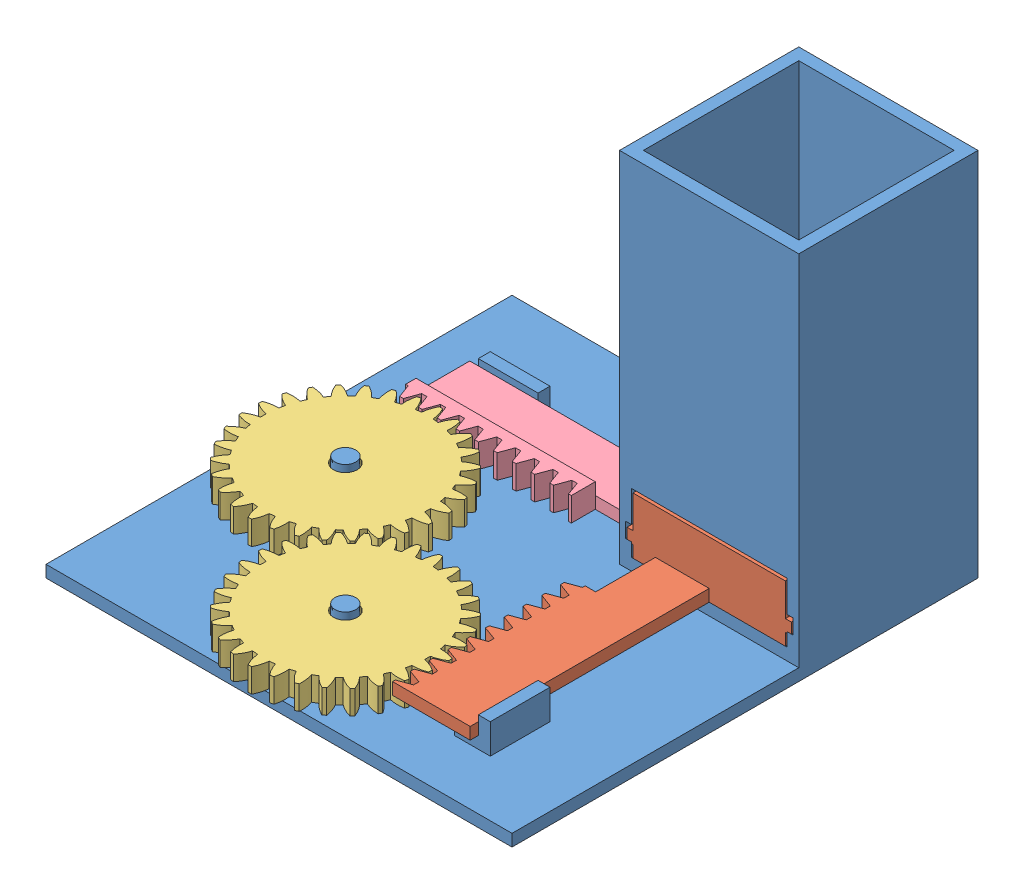
SolidWorks assembly POC_shutter, configuration Default. Lengths in mm.
Overall size (79.58 62 79.64).
5 component instances, 4 part files, 9 mates.
Components (placement in the parent):
- POC_shutter_box-1: POC_shutter_box [Default] at (21.1546 10.3571 63.6292) size (78 62 78)
- POC_shutter_wedge_w_gear-1: POC_shutter_wedge_w_gear [Default] at (95.5205 -20.2555 36.7459) x (0 0 1) z (-1 0 0) size (68 9.46 27.5)
- spur gear_am-4: spur gear_am [Metric - Spur gear 1M 30T 20PA 4FW ---S30N75H50L4N] at (17.9046 16.3571 88.2692) x (0 -1 0) z (0 0 1) size (4 31.88 32)
- spur gear_am-5: spur gear_am [Metric - Spur gear 1M 30T 20PA 4FW ---S30N75H50L4N] at (-3.4854 16.3571 66.8792) x (0 -1 0) z (0 0 1) size (4 31.88 32)
- POC_shutter_shutter_w_gear_reverse-1: POC_shutter_shutter_w_gear_reverse [Default] at (79.2798 -21.4381 18.9739) x (0 0 1) z (-1 0 0) size (27.5 4 68)
Mates (geometry in assembly coordinates):
- Symmetric2: symmetric: plane of POC_shutter_box-1 through (31.1546 10.3571 63.6292) normal (1 0 0); plane of POC_shutter_box-1 through (59.1546 10.3571 63.6292) normal (-1 0 0); plane of POC_shutter_wedge_w_gear-1 through (45.1546 14.3571 94.6292) normal (1 0 0)
- Coincident3: coincident: plane of POC_shutter_box-1 through (32.1546 10.3571 26.6292) normal (0 0 1); line of POC_shutter_wedge_w_gear-1 through (57.9046 14.3571 26.6292) axis (-1 0 0)
- Coincident8: coincident: plane of POC_shutter_box-1 through (21.1546 12.3571 63.6292) normal (0 1 0); plane of spur gear_am-4 through (17.9046 12.3571 88.2692) normal (0 -1 0)
- Coincident9: coincident: plane of POC_shutter_box-1 through (21.1546 12.3571 63.6292) normal (0 1 0); plane of spur gear_am-5 through (-3.4854 12.3571 66.8792) normal (0 -1 0)
- Concentric6: concentric: circle of POC_shutter_box-1; circle of spur gear_am-4
- Concentric7: concentric: circle of POC_shutter_box-1; circle of spur gear_am-5
- Coincident10: coincident: plane of POC_shutter_box-1 through (58.1546 10.3571 52.6292) normal (-1 0 0); plane of POC_shutter_shutter_w_gear_reverse-1 through (58.1546 14.3571 25.9446) normal (1 0 0)
- Coincident11: coincident: plane of POC_shutter_box-1 through (21.1546 12.3571 63.6292) normal (0 1 0); plane of POC_shutter_shutter_w_gear_reverse-1 through (44.1546 12.3571 39.6946) normal (0 -1 0)
- Symmetric3: symmetric: plane of POC_shutter_box-1 through (58.1546 12.3571 53.6946) normal (0 0 -1); plane of POC_shutter_box-1 through (58.1546 12.3571 25.6946) normal (0 0 1); plane of POC_shutter_shutter_w_gear_reverse-1 through (-9.8454 12.3571 39.6946) normal (0 0 -1)
